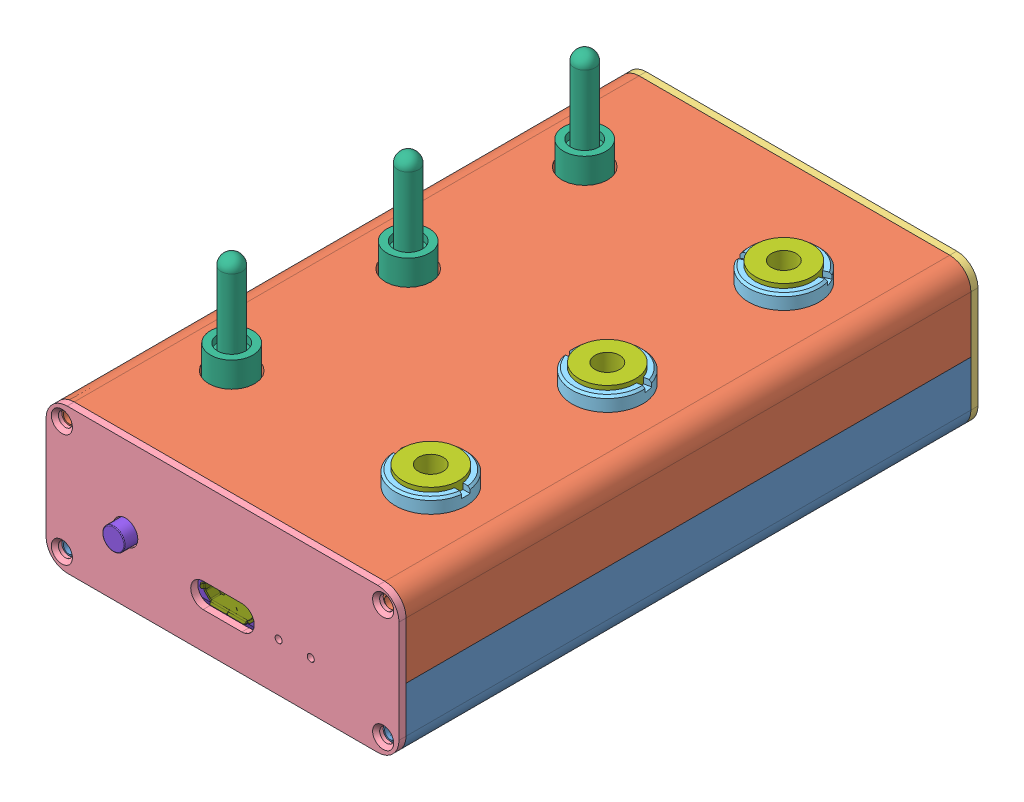
SolidWorks assembly case-full, configuration Default. Lengths in mm.
Overall size (86.14 102.52 105.97).
110 component instances, 21 part files, 23 mates.
Components (placement in the parent):
- case-1: case [Default] at (-9.9049 -10.2865 -40) size (50 11 80)
- top-case-2: top-case [Default] at (1.6835 8.41 -40) x (-1 0 0) z (0 0 1) size (50 11 80)
- case-lid-1: case-lid [Default] at (-11.7051 -0.4225 -41) size (50 20.5 1)
- case-lid-usb-1: case-lid-usb [Default] at (-11.7051 -0.4225 40) size (50 20.5 1)
- ringM8-1: ringM8 [Default] at (9.3893 9.3118 25) x (1 0 0) z (0 1 0) size (10 10 2)
- ringM8-2: ringM8 [Default] at (9.3893 9.3118 0) x (0.982082 0 -0.188455) z (0 1 0) size (10 10 2)
- ringM8-3: ringM8 [Default] at (9.3893 9.3118 -25) x (0.918365 0 -0.395734) z (0 1 0) size (10 10 2)
- PCB-assembly_v1.1-1: PCB-assembly_v1.1 [Default] at (67.1534 66.9625 123.4804) x (-0.337053 0.880168 0.334215) z (-0.925245 -0.375317 0.055309) size (66.23 89.2 52.19)
  - toggle-switch-4: toggle-switch [Default] at (-67.9927 86.0354 100.4663) x (0.334215 -0.940873 0.055309) z (0.337053 0.174117 0.925245) size (6.9 31.5 13.2)
  - 3,5mmjack_MultiComp-1: 3,5mmjack_MultiComp [Default] at (-77.3391 81.8383 75.298) x (-0.334215 0.940873 -0.055309) z (0.880168 0.290588 -0.375317) size (9 10.5 21.9)
  - ledTruckv1.1_new.step-1: ledTruckv1.1_new.step [Default] at (-61.225 73.4972 110.8928) x (-0.334215 0.940873 -0.055309) z (0.880168 0.290588 -0.375317) size (82.71 47 12.53)
    - PinHeader_1x04_P2.54mm_Vertical.step-1: PinHeader_1x04_P2.54mm_Vertical.step [Default] at (76.5862 -26.2915 1.65) x (-1 0 0) z (0 0 1) size (2.54 10.16 11.54) (hidden)
      - SOLID.step-1: SOLID.step [Default] at origin size (2.54 10.16 11.54)
    - R_0603_1608Metric.step-1: R_0603_1608Metric.step [Default] at (8.89 -22.225 1.65) x (-1 0 0) z (0 0 1) size (1.6 0.8 0.45)
      - SOLID-0.step-1: SOLID-0.step [Default] at origin size (1.6 0.8 0.45) (hidden)
    - R_0603_1608Metric.step-2: R_0603_1608Metric.step [Default] at (8.89 -24.003 1.65) size (1.6 0.8 0.45)
      - SOLID-0.step-1: SOLID-0.step [Default] at origin size (1.6 0.8 0.45) (hidden)
    - SW_Tactile_SPST_Angled_PTS645Vx58-2LFS.step-1: SW_Tactile_SPST_Angled_PTS645Vx58-2LFS.step [Default] at (3 -12 1.65) x (0 1 0) z (0 0 1) size (7.4 9.9 11)
      - SOLID-1.step-1: SOLID-1.step [Default] at origin size (7.4 9.9 11)
    - R_0603_1608Metric.step-3: R_0603_1608Metric.step [Default] at (26.416 -8.636 1.65) x (-1 0 0) z (0 0 1) size (1.6 0.8 0.45)
      - SOLID-0.step-1: SOLID-0.step [Default] at origin size (1.6 0.8 0.45) (hidden)
    - R_0603_1608Metric.step-4: R_0603_1608Metric.step [Default] at (21.082 -14.478 1.65) size (1.6 0.8 0.45)
      - SOLID-0.step-1: SOLID-0.step [Default] at origin size (1.6 0.8 0.45) (hidden)
    - R_0603_1608Metric.step-5: R_0603_1608Metric.step [Default] at (21.082 -8.636 1.65) x (-1 0 0) z (0 0 1) size (1.6 0.8 0.45)
      - SOLID-0.step-1: SOLID-0.step [Default] at origin size (1.6 0.8 0.45) (hidden)
    - R_0603_1608Metric.step-6: R_0603_1608Metric.step [Default] at (27.686 -35.052 1.65) x (-1 0 0) z (0 0 1) size (1.6 0.8 0.45)
      - SOLID-0.step-1: SOLID-0.step [Default] at origin size (1.6 0.8 0.45) (hidden)
    - SOT-23.step-1: SOT-23.step [Default] at (21.082 -4.572 1.65) x (0 -1 0) z (0 0 1) size (2.5 3 1.2)
      - SOLID-2.step-1: SOLID-2.step [Default] at origin size (2.5 3 1.2)
    - SOT-23.step-2: SOT-23.step [Default] at (31.496 -33.782 1.65) x (-1 0 0) z (0 0 1) size (2.5 3 1.2)
      - SOLID-2.step-1: SOLID-2.step [Default] at origin size (2.5 3 1.2)
    - SOT-23.step-3: SOT-23.step [Default] at (23.876 -33.782 1.65) size (2.5 3 1.2)
      - SOLID-2.step-1: SOLID-2.step [Default] at origin size (2.5 3 1.2)
    - D_SOD-323.step-1: D_SOD-323.step [Default] at (21.082 -11.684 1.65) size (2.5 1.25 1.1)
      - SOLID-3.step-1: SOLID-3.step [Default] at origin size (2.5 1.25 1.1)
    - C_0603_1608Metric.step-1: C_0603_1608Metric.step [Default] at (3.81 -3.556 1.65) size (1.6 0.8 0.8)
      - SOLID-4.step-1: SOLID-4.step [Default] at origin size (1.6 0.8 0.8) (hidden)
    - R_0603_1608Metric.step-7: R_0603_1608Metric.step [Default] at (51.938 -2.799 1.65) size (1.6 0.8 0.45)
      - SOLID-0.step-1: SOLID-0.step [Default] at origin size (1.6 0.8 0.45) (hidden)
    - SOT-23.step-4: SOT-23.step [Default] at (57.78 -3.688 1.65) x (0 -1 0) z (0 0 1) size (2.5 3 1.2)
      - SOLID-2.step-1: SOLID-2.step [Default] at origin size (2.5 3 1.2)
    - C_0603_1608Metric.step-2: C_0603_1608Metric.step [Default] at (51.938 -4.45 1.65) x (-1 0 0) z (0 0 1) size (1.6 0.8 0.8)
      - SOLID-4.step-1: SOLID-4.step [Default] at origin size (1.6 0.8 0.8) (hidden)
    - SOT-23-5.step-1: SOT-23-5.step [Default] at (32.126 -4.704 1.65) x (0 -1 0) z (0 0 1) size (2.8 2.9 1.55)
      - SOLID-5.step-1: SOLID-5.step [Default] at origin size (2.8 2.9 1.55)
    - SOT-23-5.step-2: SOT-23-5.step [Default] at (26.416 -4.699 1.65) x (0 -1 0) z (0 0 1) size (2.8 2.9 1.55)
      - SOLID-5.step-1: SOLID-5.step [Default] at origin size (2.8 2.9 1.55)
    - JST_PH_S2B-PH-K_1x02_P2.00mm_Horizontal.step-1: JST_PH_S2B-PH-K_1x02_P2.00mm_Horizontal.step [Default] at (74.544 -6.228 1.65) size (5.9 7.6 8.25)
      - SOLID-6.step-1: SOLID-6.step [Default] at origin size (5.9 7.6 8.25)
    - R_0603_1608Metric.step-8: R_0603_1608Metric.step [Default] at (57.1958 -32.8676 1.65) x (-1 0 0) z (0 0 1) size (1.6 0.8 0.45)
      - SOLID-0.step-1: SOLID-0.step [Default] at origin size (1.6 0.8 0.45) (hidden)
    - R_0603_1608Metric.step-9: R_0603_1608Metric.step [Default] at (57.526 -8.006 1.65) size (1.6 0.8 0.45)
      - SOLID-0.step-1: SOLID-0.step [Default] at origin size (1.6 0.8 0.45) (hidden)
    - R_0603_1608Metric.step-10: R_0603_1608Metric.step [Default] at (57.526 -6.355 1.65) x (-1 0 0) z (0 0 1) size (1.6 0.8 0.45)
      - SOLID-0.step-1: SOLID-0.step [Default] at origin size (1.6 0.8 0.45) (hidden)
    - R_0603_1608Metric.step-11: R_0603_1608Metric.step [Default] at (5.969 -36.068 1.65) x (0 -1 0) z (0 0 1) size (1.6 0.8 0.45)
      - SOLID-0.step-1: SOLID-0.step [Default] at origin size (1.6 0.8 0.45) (hidden)
    - R_0603_1608Metric.step-12: R_0603_1608Metric.step [Default] at (5.9944 -31.4706 1.65) x (0 1 0) z (0 0 1) size (1.6 0.8 0.45)
      - SOLID-0.step-1: SOLID-0.step [Default] at origin size (1.6 0.8 0.45) (hidden)
    - R_0603_1608Metric.step-13: R_0603_1608Metric.step [Default] at (46.604 -7.752 1.65) size (1.6 0.8 0.45)
      - SOLID-0.step-1: SOLID-0.step [Default] at origin size (1.6 0.8 0.45) (hidden)
    - R_0603_1608Metric.step-14: R_0603_1608Metric.step [Default] at (59.812 -12.705 1.65) x (0 1 0) z (0 0 1) size (1.6 0.8 0.45)
      - SOLID-0.step-1: SOLID-0.step [Default] at origin size (1.6 0.8 0.45) (hidden)
    - R_0603_1608Metric.step-15: R_0603_1608Metric.step [Default] at (32.1514 -8.636 1.65) x (-1 0 0) z (0 0 1) size (1.6 0.8 0.45)
      - SOLID-0.step-1: SOLID-0.step [Default] at origin size (1.6 0.8 0.45) (hidden)
    - R_0603_1608Metric.step-16: R_0603_1608Metric.step [Default] at (51.938 -38.994 1.65) x (-1 0 0) z (0 0 1) size (1.6 0.8 0.45)
      - SOLID-0.step-1: SOLID-0.step [Default] at origin size (1.6 0.8 0.45) (hidden)
    - R_0603_1608Metric.step-17: R_0603_1608Metric.step [Default] at (51.938 -34.93 1.65) size (1.6 0.8 0.45)
      - SOLID-0.step-1: SOLID-0.step [Default] at origin size (1.6 0.8 0.45) (hidden)
    - R_0603_1608Metric.step-18: R_0603_1608Metric.step [Default] at (27.686 -36.957 1.65) size (1.6 0.8 0.45)
      - SOLID-0.step-1: SOLID-0.step [Default] at origin size (1.6 0.8 0.45) (hidden)
    - R_0603_1608Metric.step-19: R_0603_1608Metric.step [Default] at (51.938 -36.962 1.65) x (-1 0 0) z (0 0 1) size (1.6 0.8 0.45)
      - SOLID-0.step-1: SOLID-0.step [Default] at origin size (1.6 0.8 0.45) (hidden)
    - R_0603_1608Metric.step-20: R_0603_1608Metric.step [Default] at (51.9176 -32.9184 1.65) x (-1 0 0) z (0 0 1) size (1.6 0.8 0.45)
      - SOLID-0.step-1: SOLID-0.step [Default] at origin size (1.6 0.8 0.45) (hidden)
    - R_0603_1608Metric.step-21: R_0603_1608Metric.step [Default] at (27.686 -38.862 1.65) size (1.6 0.8 0.45)
      - SOLID-0.step-1: SOLID-0.step [Default] at origin size (1.6 0.8 0.45) (hidden)
    - C_0805_2012Metric.step-1: C_0805_2012Metric.step [Default] at (26.416 -14.478 1.65) x (-1 0 0) z (0 0 1) size (2 1.25 1.25)
      - SOLID-7.step-1: SOLID-7.step [Default] at origin size (2 1.25 1.25)
    - C_0603_1608Metric.step-3: C_0603_1608Metric.step [Default] at (46.604 -6.101 1.65) x (-1 0 0) z (0 0 1) size (1.6 0.8 0.8)
      - SOLID-4.step-1: SOLID-4.step [Default] at origin size (1.6 0.8 0.8) (hidden)
    - C_0805_2012Metric.step-2: C_0805_2012Metric.step [Default] at (32.126 -11.689 1.65) size (2 1.25 1.25)
      - SOLID-7.step-1: SOLID-7.step [Default] at origin size (2 1.25 1.25)
    - C_0603_1608Metric.step-4: C_0603_1608Metric.step [Default] at (46.604 -4.45 1.65) size (1.6 0.8 0.8)
      - SOLID-4.step-1: SOLID-4.step [Default] at origin size (1.6 0.8 0.8) (hidden)
    - C_0603_1608Metric.step-5: C_0603_1608Metric.step [Default] at (46.604 -2.799 1.65) size (1.6 0.8 0.8)
      - SOLID-4.step-1: SOLID-4.step [Default] at origin size (1.6 0.8 0.8) (hidden)
    - C_0805_2012Metric.step-3: C_0805_2012Metric.step [Default] at (26.416 -11.684 1.65) x (-1 0 0) z (0 0 1) size (2 1.25 1.25)
      - SOLID-7.step-1: SOLID-7.step [Default] at origin size (2 1.25 1.25)
    - C_0603_1608Metric.step-6: C_0603_1608Metric.step [Default] at (57.526 -9.657 1.65) size (1.6 0.8 0.8)
      - SOLID-4.step-1: SOLID-4.step [Default] at origin size (1.6 0.8 0.8) (hidden)
    - C_0603_1608Metric.step-7: C_0603_1608Metric.step [Default] at (57.526 -15.626 1.65) size (1.6 0.8 0.8)
      - SOLID-4.step-1: SOLID-4.step [Default] at origin size (1.6 0.8 0.8) (hidden)
    - C_0805_2012Metric.step-4: C_0805_2012Metric.step [Default] at (32.126 -14.478 1.65) size (2 1.25 1.25)
      - SOLID-7.step-1: SOLID-7.step [Default] at origin size (2 1.25 1.25)
    - LED_0805_2012Metric.step-1: LED_0805_2012Metric.step [Default] at (2.6589 -36 1.65) x (0 -1 0) z (0 0 1) size (2 1.25 1.1)
      - SOLID-8.step-1: SOLID-8.step [Default] at origin size (2 1.25 1.1)
    - LED_0805_2012Metric.step-2: LED_0805_2012Metric.step [Default] at (2.6589 -31.45 1.65) x (0 -1 0) z (0 0 1) size (2 1.25 1.1)
      - SOLID-8.step-1: SOLID-8.step [Default] at origin size (2 1.25 1.1)
    - QFN-32-1EP_4x4mm_P0.4mm_EP2.65x2.65mm.step-1: QFN-32-1EP_4x4mm_P0.4mm_EP2.65x2.65mm.step [Default] at (49.136 -12.5 1.65) x (-1 0 0) z (0 0 1) size (4 4 0.92)
      - SOLID-9.step-1: SOLID-9.step [Default] at origin size (4 4 0.92)
    - USB_Micro-B_Molex_47346-0001.step-1: USB_Micro-B_Molex_47346-0001.step [Default] at (3.3873 -23.4924 1.65) x (0 -1 0) z (0 0 1) size (7.98 5.42 2.94)
      - SOLID-10.step-1: SOLID-10.step [Default] at origin size (7.98 5.42 2.94)
    - Crystal_SMD_0603-4Pin_6.0x3.5mm.step-1: Crystal_SMD_0603-4Pin_6.0x3.5mm.step [Default] at (57.526 -12.705 1.65) x (0 1 0) z (0 0 1) size (6 3.5 1.03)
      - SOLID-11.step-1: SOLID-11.step [Default] at origin size (6 3.5 1.03) (hidden)
    - COMPOUND.step-1: COMPOUND.step [Default] at origin size (80 47 1.6)
  - toggle-switch-5: toggle-switch [Default] at (-76.348 109.5572 99.0835) x (0.334215 -0.940873 0.055309) z (0.337053 0.174117 0.925245) size (6.9 31.5 13.2)
  - toggle-switch-6: toggle-switch [Default] at (-84.7034 133.079 97.7008) x (0.334215 -0.940873 0.055309) z (0.337053 0.174117 0.925245) size (6.9 31.5 13.2)
  - 3,5mmjack_MultiComp-6: 3,5mmjack_MultiComp [Default] at (-85.6945 105.3601 73.9153) x (-0.334215 0.940873 -0.055309) z (0.880168 0.290588 -0.375317) size (9 10.5 21.9)
  - 3,5mmjack_MultiComp-7: 3,5mmjack_MultiComp [Default] at (-94.0499 128.882 72.5326) x (-0.334215 0.940873 -0.055309) z (0.880168 0.290588 -0.375317) size (9 10.5 21.9)
Mates (geometry in assembly coordinates):
- Coincident1: coincident aligned: plane of case-1 through (-27.6107 -2.4882 40) normal (1 0 0); plane of top-case-2 through (-27.6107 2.6118 40) normal (1 0 0)
- Coincident3: coincident aligned: plane of case-1 through (-27.6107 -2.4882 40) normal (1 0 0); plane of top-case-2 through (-27.6107 2.6118 40) normal (1 0 0)
- Parallel2: parallel aligned: plane of case-1 through (19.3893 -4.4882 40) normal (-1 0 0); plane of top-case-2 through (19.3893 0.6118 40) normal (-1 0 0)
- Coincident6: coincident anti-aligned: plane of case-1 through (19.8933 -1.6882 40) normal (0 1 0); plane of top-case-2 through (20.8893 -1.6882 40) normal (0 -1 0)
- Coincident7: coincident aligned: plane of case-1 through (-26.1107 -8.1882 40) normal (0 0 1); plane of top-case-2 through (17.8893 6.3118 40) normal (0 0 1)
- Coincident9: coincident anti-aligned: plane of case-1 through (-27.6107 -5.4882 40) normal (1 0 0); plane of PCB-assembly-1/ledTruck_PCB.step-1/ledTruck.step-1/COMPOUND.step-1 through (-27.6107 -7.0882 40) normal (-1 0 0)
- Coincident10: coincident anti-aligned: plane of case-1 through (19.3893 -5.4882 40) normal (0 -1 0); plane of PCB-assembly-1/ledTruck_PCB.step-1/ledTruck.step-1/COMPOUND.step-1 through (-4.1107 -5.4882 0) normal (0 1 0)
- Coincident11: coincident aligned: plane of case-1 through (-26.1107 -8.1882 40) normal (0 0 1); plane of PCB-assembly-1/ledTruck_PCB.step-1/ledTruck.step-1/COMPOUND.step-1 through (19.3893 -7.0882 40) normal (0 0 1)
- Coincident12: coincident anti-aligned: plane of top-case-2 through (17.8893 6.3118 -40) normal (0 0 -1); plane of case-lid-1 through (17.8893 6.3118 -40) normal (0 0 1)
- Coincident13: coincident aligned: plane of top-case-2 through (17.8893 9.3118 40) normal (0 1 0); plane of case-lid-1 through (-26.1107 9.3118 -40) normal (0 1 0)
- Coincident14: coincident aligned: plane of case-1 through (-29.1107 -0.1882 40) normal (-1 0 0); plane of case-lid-1 through (-29.1107 6.3118 -40) normal (-1 0 0)
- Coincident15: coincident anti-aligned: plane of top-case-2 through (17.8893 6.3118 40) normal (0 0 1); plane of case-lid-usb-1 through (17.8893 6.3118 40) normal (0 0 -1)
- Coincident16: coincident aligned: plane of top-case-2 through (17.8893 9.3118 40) normal (0 1 0); plane of case-lid-usb-1 through (-26.1107 9.3118 41) normal (0 1 0)
- Coincident18: coincident aligned: plane of top-case-2 through (-29.1107 6.3118 40) normal (-1 0 0); plane of case-lid-usb-1 through (-29.1107 6.3118 41) normal (-1 0 0)
- Coincident19: coincident anti-aligned: plane of top-case-2 through (17.8893 9.3118 40) normal (0 1 0); plane of ringM8-1 through (9.3893 9.3118 25) normal (0 -1 0)
- Concentric1: concentric anti-aligned: cylinder of PCB-assembly-1/3,5mmjack_MultiComp-1 through (9.3893 28.9343 25) axis (0 -1 0) radius 4; circle of ringM8-1
- Coincident20: coincident anti-aligned: plane of top-case-2 through (17.8893 9.3118 40) normal (0 1 0); plane of ringM8-2 through (9.3893 9.3118 0) normal (0 -1 0)
- Concentric2: concentric anti-aligned: cylinder of PCB-assembly-1/3,5mmjack_MultiComp-4 through (9.3893 12.0118 0) axis (0 -1 0) radius 4; circle of ringM8-2
- Coincident21: coincident anti-aligned: plane of top-case-2 through (17.8893 9.3118 40) normal (0 1 0); plane of ringM8-3 through (9.3893 9.3118 -25) normal (0 -1 0)
- Concentric3: concentric anti-aligned: cylinder of PCB-assembly-1/3,5mmjack_MultiComp-5 through (9.3893 12.0118 -25) axis (0 -1 0) radius 4; circle of ringM8-3
- Coincident22: coincident anti-aligned: plane of case-1 through (-27.6107 -5.4882 40) normal (1 0 0); plane of PCB-assembly_v1.1-1/ledTruckv1.1_new.step-1/COMPOUND.step-1 through (-27.6107 -7.1882 40) normal (-1 0 0)
- Coincident23: coincident anti-aligned: plane of case-1 through (-26.4107 -7.1882 40) normal (0 1 0); plane of PCB-assembly_v1.1-1/ledTruckv1.1_new.step-1/COMPOUND.step-1 through (-4.1107 -7.1882 0) normal (0 -1 0)
- Coincident24: coincident aligned: plane of case-1 through (-26.1107 -8.1882 40) normal (0 0 1); plane of PCB-assembly_v1.1-1/ledTruckv1.1_new.step-1/COMPOUND.step-1 through (19.3893 -7.1882 40) normal (0 0 1)
